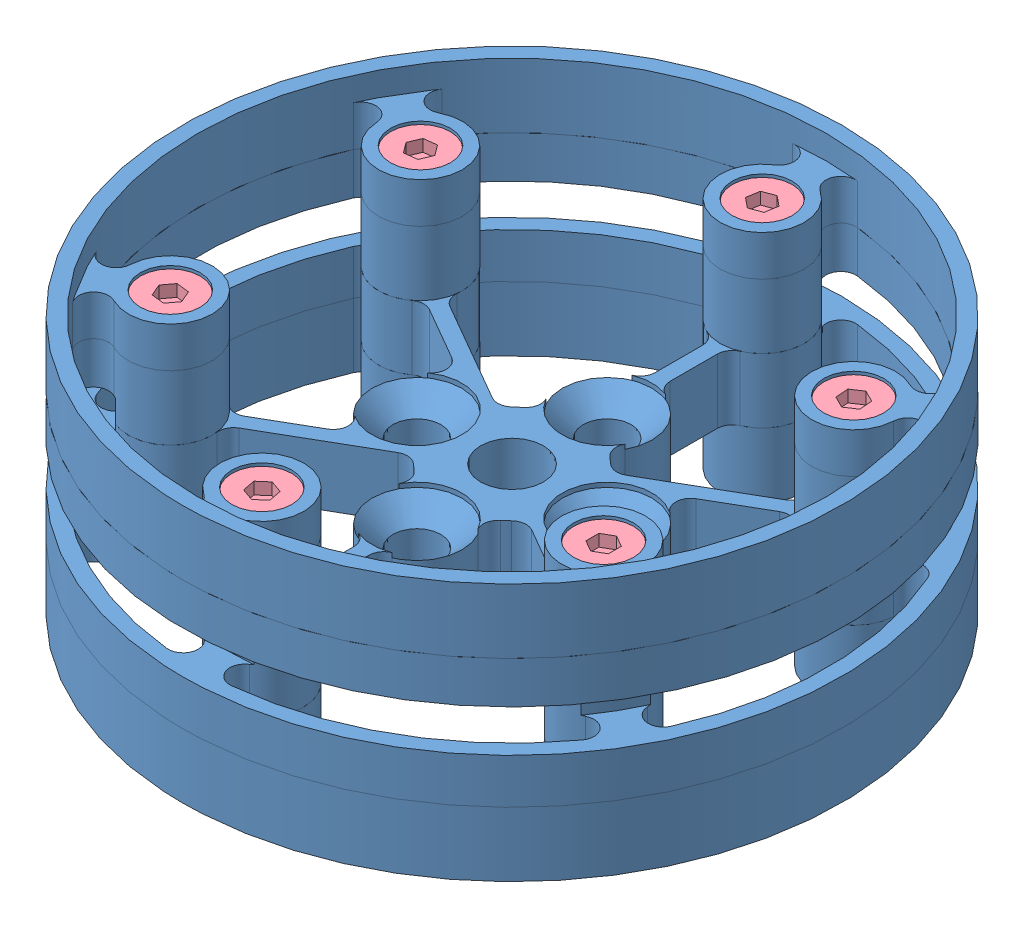
SolidWorks assembly wheel-powered, configuration Default. Lengths in mm.
Overall size (60.11 17.2 60.11).
22 component instances, 4 part files, 33 mates.
Components (placement in the parent):
- wheel-1: wheel [Powered middle mount] at origin size (44 4.3 44)
- wheel-2: wheel [Powered inner] at (0 -4.3 0) size (44 4.3 44)
- insert-m2-4mm-1: insert-m2-4mm [Default] at (-14.4626 2.8 -8.35) size (3.2 3 3.18)
- insert-m2-4mm-2: insert-m2-4mm [Default] at (0 2.8 -16.7) x (0.982082 0 -0.188455) z (0.188455 0 0.982082) size (3.2 3 3.18)
- insert-m2-4mm-3: insert-m2-4mm [Default] at (14.4626 2.8 -8.35) x (0.918365 0 -0.395734) z (0.395734 0 0.918365) size (3.2 3 3.18)
- insert-m2-4mm-4: insert-m2-4mm [Default] at (14.4626 2.8 8.35) x (0.8 0 -0.6) z (0.6 0 0.8) size (3.2 3 3.18)
- insert-m2-4mm-5: insert-m2-4mm [Default] at (0 2.8 16.7) x (0.63358 0 -0.773678) z (0.773678 0 0.63358) size (3.2 3 3.18)
- insert-m2-4mm-6: insert-m2-4mm [Default] at (-14.4626 2.8 8.35) x (0.443629 0 -0.896211) z (0.896211 0 0.443629) size (3.2 3 3.18)
- countersunk-screw-m2-6mm-1: countersunk-screw-m2-6mm [Default] at (-14.4626 -4.1 8.35) x (0 1 0) z (0 0 1) size (6 4 4)
- countersunk-screw-m2-6mm-2: countersunk-screw-m2-6mm [Default] at (0 -4.1 16.7) x (0 1 0) z (0.188455 0 0.982082) size (6 4 4)
- countersunk-screw-m2-6mm-4: countersunk-screw-m2-6mm [Default] at (14.4626 -4.1 8.35) x (0 1 0) z (0.395734 0 0.918365) size (6 4 4)
- countersunk-screw-m2-6mm-6: countersunk-screw-m2-6mm [Default] at (14.4626 -4.1 -8.35) x (0 1 0) z (0.6 0 0.8) size (6 4 4)
- countersunk-screw-m2-6mm-8: countersunk-screw-m2-6mm [Default] at (0 -4.1 -16.7) x (0 1 0) z (0.773678 0 0.63358) size (6 4 4)
- countersunk-screw-m2-6mm-10: countersunk-screw-m2-6mm [Default] at (-14.4626 -4.1 -8.35) x (0 1 0) z (0.896211 0 0.443629) size (6 4 4)
- wheel-3: wheel [Free middle] at (0 8.6 0) x (-0.5 0 -0.866025) z (-0.866025 0 0.5) size (44 4.3 44)
- wheel-4: wheel [Free outer] at (0 8.6 0) size (44 4.3 44)
- countersunk-screw-m2-10mm-1: countersunk-screw-m2-10mm [Default] at (14.4626 11.1 8.35) x (0 -1 0) z (0 0 1) size (10 4 4)
- countersunk-screw-m2-10mm-2: countersunk-screw-m2-10mm [Default] at (0 11.1 16.7) x (0 -1 0) z (0.188455 0 0.982082) size (10 4 4)
- countersunk-screw-m2-10mm-4: countersunk-screw-m2-10mm [Default] at (-14.4626 11.1 8.35) x (0 -1 0) z (0.395734 0 0.918365) size (10 4 4)
- countersunk-screw-m2-10mm-6: countersunk-screw-m2-10mm [Default] at (-14.4626 11.1 -8.35) x (0 -1 0) z (0.6 0 0.8) size (10 4 4)
- countersunk-screw-m2-10mm-8: countersunk-screw-m2-10mm [Default] at (0 11.1 -16.7) x (0 -1 0) z (0.773678 0 0.63358) size (10 4 4)
- countersunk-screw-m2-10mm-10: countersunk-screw-m2-10mm [Default] at (14.4626 11.1 -8.35) x (0 -1 0) z (0.896211 0 0.443629) size (10 4 4)
Mates (geometry in assembly coordinates):
- Concentric1: concentric: cylinder of wheel-1 through (0 -0.001 -16.7) axis (0 1 0) radius 1.8; cylinder of wheel-2 through (0 0.001 -16.7) axis (0 -1 0) radius 1.1
- Concentric2: concentric: cylinder of wheel-1 through (0 -0.001 16.7) axis (0 1 0) radius 1.8; cylinder of wheel-2 through (0 0.001 16.7) axis (0 -1 0) radius 1.1
- Coincident1: coincident: plane of wheel-1 through (0 0 0) normal (0 -1 0); plane of wheel-2 through (0 0 0) normal (0 1 0)
- Concentric3: concentric: cylinder of wheel-1 through (-14.4626 -0.001 -8.35) axis (0 1 0) radius 1.8; cylinder of insert-m2-4mm-1 through (-14.4626 4.3 -8.35) axis (0 -1 0) radius 1
- Coincident2: coincident: plane of wheel-1 through (0 4.3 0) normal (0 1 0); plane of insert-m2-4mm-1 through (-14.4626 4.3 -8.35) normal (0 1 0)
- Coincident3: coincident: plane of wheel-1 through (0 4.3 0) normal (0 1 0); plane of insert-m2-4mm-2 through (0 4.3 -16.7) normal (0 1 0)
- Concentric4: concentric: cylinder of wheel-1 through (0 -0.001 -16.7) axis (0 1 0) radius 1.8; cylinder of insert-m2-4mm-2 through (0 4.3 -16.7) axis (0 -1 0) radius 1
- Coincident4: coincident: plane of wheel-1 through (0 4.3 0) normal (0 1 0); plane of insert-m2-4mm-3 through (14.4626 4.3 -8.35) normal (0 1 0)
- Concentric5: concentric: cylinder of wheel-1 through (14.4626 -0.001 -8.35) axis (0 1 0) radius 1.8; cylinder of insert-m2-4mm-3 through (14.4626 4.3 -8.35) axis (0 -1 0) radius 1
- Coincident5: coincident: plane of wheel-1 through (0 4.3 0) normal (0 1 0); plane of insert-m2-4mm-4 through (14.4626 4.3 8.35) normal (0 1 0)
- Concentric6: concentric: cylinder of wheel-1 through (14.4626 -0.001 8.35) axis (0 1 0) radius 1.8; cylinder of insert-m2-4mm-4 through (14.4626 4.3 8.35) axis (0 -1 0) radius 1
- Coincident6: coincident: plane of wheel-1 through (0 4.3 0) normal (0 1 0); plane of insert-m2-4mm-5 through (0 4.3 16.7) normal (0 1 0)
- Concentric7: concentric: cylinder of wheel-1 through (0 -0.001 16.7) axis (0 1 0) radius 1.8; cylinder of insert-m2-4mm-5 through (0 4.3 16.7) axis (0 -1 0) radius 1
- Coincident7: coincident: plane of wheel-1 through (0 4.3 0) normal (0 1 0); plane of insert-m2-4mm-6 through (-14.4626 4.3 8.35) normal (0 1 0)
- Concentric8: concentric: cylinder of wheel-1 through (-14.4626 -0.001 8.35) axis (0 1 0) radius 1.8; cylinder of insert-m2-4mm-6 through (-14.4626 4.3 8.35) axis (0 -1 0) radius 1
- Coincident9: coincident: cone of wheel-2 through (-14.4626 -4 8.35) axis (0 1 0); cone of countersunk-screw-m2-6mm-1 through (-14.4626 -3 8.35) axis (0 1 0)
- Coincident10: coincident: cone of wheel-2 through (0 -4 16.7) axis (0 1 0); cone of countersunk-screw-m2-6mm-2 through (0 -3 16.7) axis (0 1 0)
- Coincident11: coincident: cone of wheel-2 through (14.4626 -4 8.35) axis (0 1 0); cone of countersunk-screw-m2-6mm-4 through (14.4626 -3 8.35) axis (0 1 0)
- Coincident12: coincident: cone of wheel-2 through (14.4626 -4 -8.35) axis (0 1 0); cone of countersunk-screw-m2-6mm-6 through (14.4626 -3 -8.35) axis (0 1 0)
- Coincident13: coincident: cone of wheel-2 through (0 -4 -16.7) axis (0 1 0); cone of countersunk-screw-m2-6mm-8 through (0 -3 -16.7) axis (0 1 0)
- Coincident14: coincident: cone of wheel-2 through (-14.4626 -4 -8.35) axis (0 1 0); cone of countersunk-screw-m2-6mm-10 through (-14.4626 -3 -8.35) axis (0 1 0)
- Coincident15: coincident: plane of wheel-1 through (0 4.3 0) normal (0 1 0); plane of wheel-3 through (0 4.3 0) normal (0 -1 0)
- Concentric9: concentric: cylinder of wheel-1 through (0 -0.001 16.7) axis (0 1 0) radius 1.8; cylinder of wheel-3 through (0 8.601 16.7) axis (0 -1 0) radius 1.1
- Concentric10: concentric: cylinder of wheel-1 through (0 -0.001 -16.7) axis (0 1 0) radius 1.8; cylinder of wheel-3 through (0 8.601 -16.7) axis (0 -1 0) radius 1.1
- Coincident16: coincident: plane of wheel-3 through (0 8.6 0) normal (0 1 0); plane of wheel-4 through (0 8.6 0) normal (0 -1 0)
- Concentric11: concentric: cylinder of wheel-3 through (14.4626 8.601 8.35) axis (0 -1 0) radius 1.1; cylinder of wheel-4 through (14.4626 11.3 8.35) axis (0 1 0) radius 1.1
- Concentric12: concentric: cylinder of wheel-3 through (-14.4626 8.601 -8.35) axis (0 -1 0) radius 1.1; cylinder of wheel-4 through (-14.4626 11.3 -8.35) axis (0 1 0) radius 1.1
- Coincident17: coincident: cone of wheel-4 through (14.4626 11 8.35) axis (0 -1 0); cone of countersunk-screw-m2-10mm-1 through (14.4626 10 8.35) axis (0 -1 0)
- Coincident18: coincident: cone of wheel-4 through (0 11 16.7) axis (0 -1 0); cone of countersunk-screw-m2-10mm-2 through (0 10 16.7) axis (0 -1 0)
- Coincident19: coincident: cone of wheel-4 through (-14.4626 11 8.35) axis (0 -1 0); cone of countersunk-screw-m2-10mm-4 through (-14.4626 10 8.35) axis (0 -1 0)
- Coincident20: coincident: cone of wheel-4 through (-14.4626 11 -8.35) axis (0 -1 0); cone of countersunk-screw-m2-10mm-6 through (-14.4626 10 -8.35) axis (0 -1 0)
- Coincident21: coincident: cone of wheel-4 through (0 11 -16.7) axis (0 -1 0); cone of countersunk-screw-m2-10mm-8 through (0 10 -16.7) axis (0 -1 0)
- Coincident22: coincident: cone of wheel-4 through (14.4626 11 -8.35) axis (0 -1 0); cone of countersunk-screw-m2-10mm-10 through (14.4626 10 -8.35) axis (0 -1 0)
